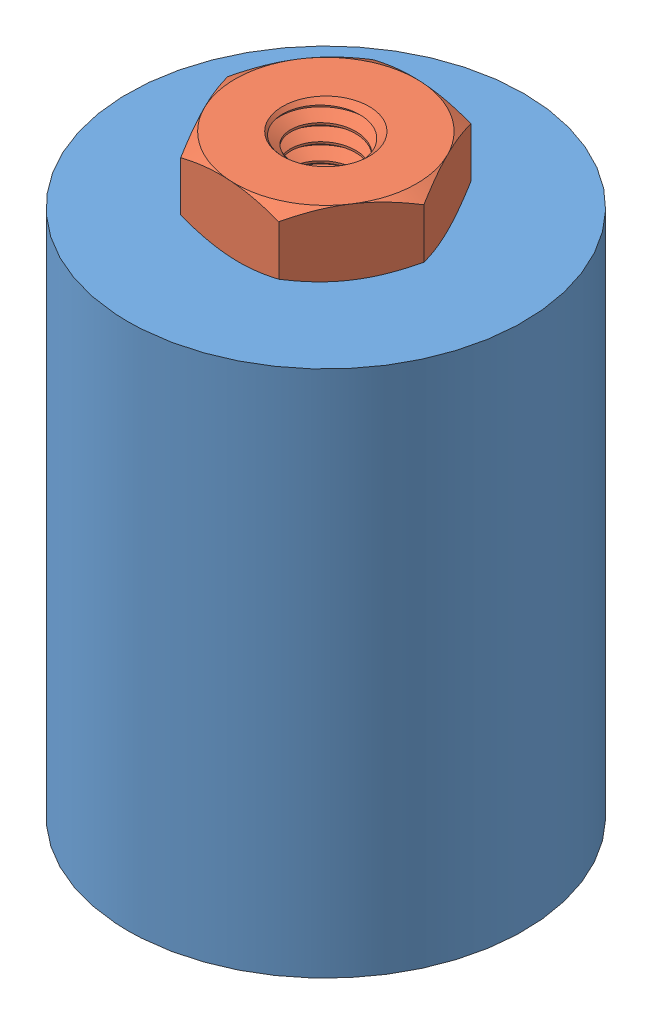
SolidWorks assembly Dyn Counterweight Stackup, configuration Default. Lengths in mm.
Overall size (25.4 32.36 25.4).
3 component instances, 2 part files, 4 mates.
Components (placement in the parent):
- custom counterweight-1: custom counterweight [Default] at (8.0633 -37.9919 12.928) size (25.4 25.4 25.4)
- 8-32 hex nut-1: 8-32 hex nut [90480A009] at (8.0633 -11.0044 12.928) x (-0.895271 0 0.445521) z (-0.445521 0 -0.895271) size (8.73 3.79 10.08)
- 8-32 hex nut-2: 8-32 hex nut [90480A009] at (8.0633 -39.5794 12.928) x (-0.895271 0 0.445521) z (-0.445521 0 -0.895271) size (8.73 3.79 10.08)
Mates (geometry in assembly coordinates):
- Coincident1: coincident aligned: plane of custom counterweight-1 through (8.0633 -12.5919 12.928) normal (0 1 0); circle of 8-32 hex nut-1
- Concentric1: concentric aligned: circle of custom counterweight-1; circle of 8-32 hex nut-1
- Concentric2: concentric aligned: circle of custom counterweight-1; circle of 8-32 hex nut-2
- Coincident2: coincident anti-aligned: plane of custom counterweight-1 through (8.0633 -37.9919 12.928) normal (0 -1 0); plane of 8-32 hex nut-2 through (13.0946 -37.9919 13.2396) normal (0 1 0)
